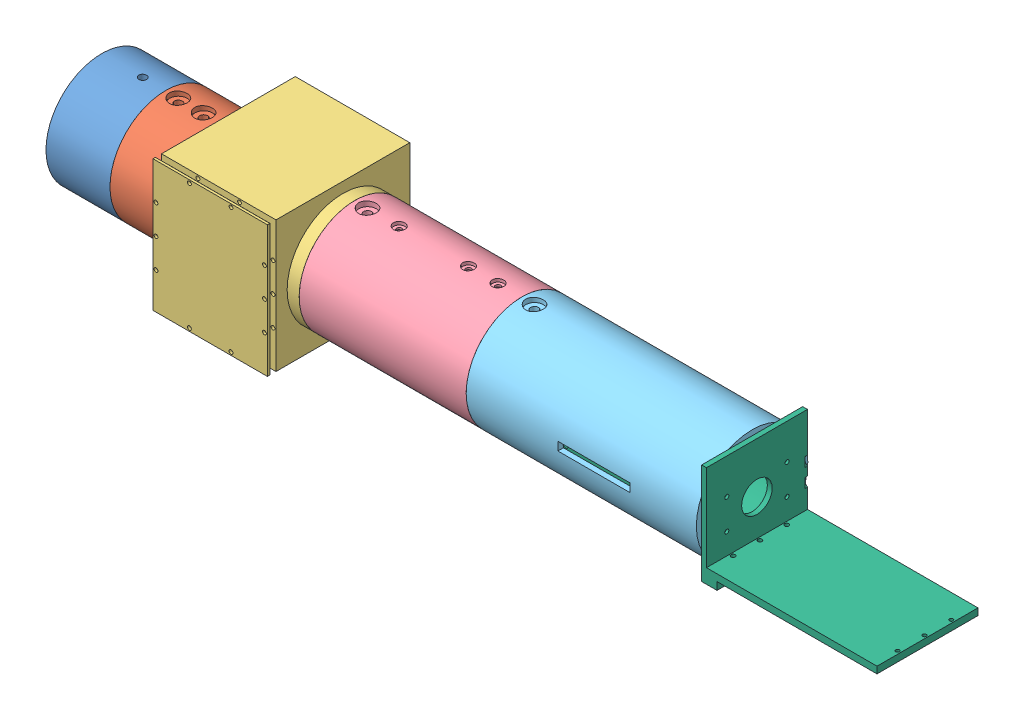
SolidWorks assembly helium_IR_polarimeter_assembly, configuration Default. Lengths in mm.
Overall size (685.18 109 118.08).
6 component instances, 6 part files, 10 mates.
Components (placement in the parent):
- connector_ring-1: connector_ring [Default] at (-58.5413 130.3415 -5.274) x (0 0 1) z (-1 0 0) size (92.5 92.5 53.1)
- collimating_lens_new-1: collimating_lens_new [Default] at (9.2734 120.7986 -5.274) x (0 0 1) z (-1 0 0) size (92.5 92.5 90.1)
- fabry_perot_modified_for_prof_ren_V2-3: fabry_perot_modified_for_prof_ren_V2 [Default] at (124.8038 92 50.226) size (115 109 118.08)
- polarimeter_tube_final-3: polarimeter_tube_final [Default] at (135.1591 128.75 -5.274) x (0 0 1) z (-1 0 0) size (92.5 92.5 148.58)
- imaging_lens-2: imaging_lens [Default] at (332.9514 120.2986 -5.274) x (0 0 1) z (-1 0 0) size (92.5 92.5 201)
- camera_holding_new-2: camera_holding_new [Default] at (581.4072 50.062 2.1373) x (-1 0 0) z (0 0 -1) size (315.5 83.82 83.82)
Mates (geometry in assembly coordinates):
- Concentric1: concentric aligned: circle of connector_ring-1; circle of collimating_lens_new-1
- Coincident1: coincident anti-aligned: plane of connector_ring-1 through (-11.841 138.75 -5.274) normal (1 0 0); plane of collimating_lens_new-1 through (-11.841 138.75 -5.274) normal (-1 0 0)
- Concentric2: concentric anti-aligned: circle of collimating_lens_new-1; circle of fabry_perot_modified_for_prof_ren_V2-3
- Coincident2: coincident anti-aligned: plane of collimating_lens_new-1 through (40.1591 133.75 -5.274) normal (1 0 0); plane of fabry_perot_modified_for_prof_ren_V2-3 through (40.1591 147 -60.774) normal (-1 0 0)
- Concentric3: concentric anti-aligned: circle of fabry_perot_modified_for_prof_ren_V2-3; circle of polarimeter_tube_final-3
- Coincident3: coincident anti-aligned: plane of fabry_perot_modified_for_prof_ren_V2-3 through (145.1591 92 -5.274) normal (1 0 0); plane of polarimeter_tube_final-3 through (145.1591 133.75 -5.274) normal (-1 0 0)
- Concentric4: concentric aligned: circle of polarimeter_tube_final-3; circle of imaging_lens-2
- Coincident4: coincident anti-aligned: plane of polarimeter_tube_final-3 through (283.737 138.25 -5.274) normal (1 0 0); circle of imaging_lens-2
- Coincident5: coincident anti-aligned: plane of imaging_lens-2 through (304.737 127 -5.274) normal (1 0 0); plane of camera_holding_new-2 through (304.737 92 -5.274) normal (-1 0 0)
- Concentric6: concentric aligned: circle of imaging_lens-2; circle of camera_holding_new-2
